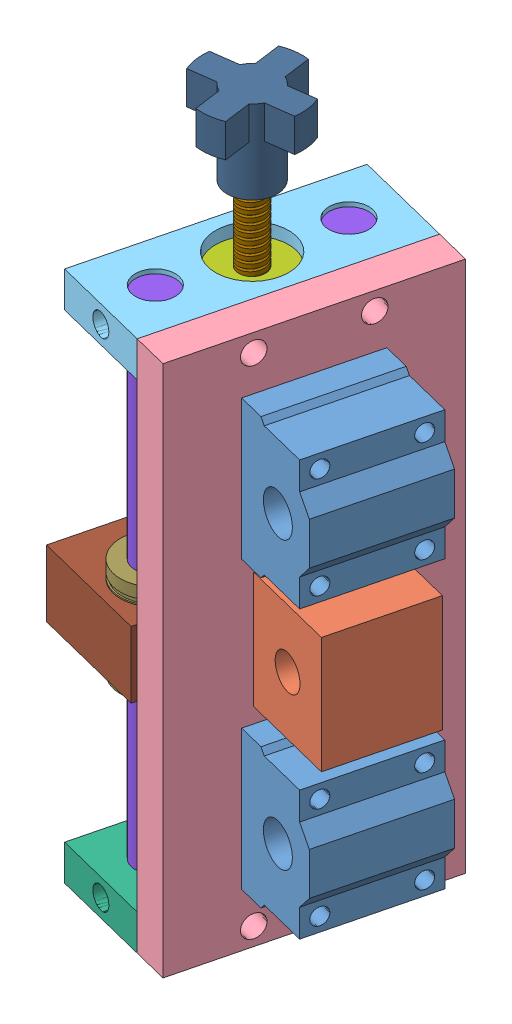
SolidWorks assembly MaquinaEixoZ, configuration Valor predeterminado. Lengths in mm.
Overall size (87.41 203.7 84.47).
17 component instances, 12 part files, 41 mates.
Components (placement in the parent):
- PillowBlockSCS12UU_12mm-5: PillowBlockSCS12UU_12mm [Valor predeterminado] at (292.0483 170.0438 408.5046) x (0 -1 0) z (0.243103 0 -0.970001) size (42 28 36)
- PillowBlockSCS12UU_12mm-6: PillowBlockSCS12UU_12mm [Valor predeterminado] at (292.0483 84.0438 408.5046) x (0 -1 0) z (0.243103 0 -0.970001) size (42 28 36)
- SuporteCastanhaTr8-2: SuporteCastanhaTr8 [Valor predeterminado] at (285.0293 127.0438 403.6528) x (0 -1 0) z (0.243103 0 -0.970001) size (35 28 30)
- CastanhaTr8_2mm-2: CastanhaTr8_2mm [Valor predeterminado] at (250.1666 126.6014 379.4525) x (0.227841 0 -0.973698) z (0 1 0) size (22 22 15.4)
- ChapaBaseEixoZ-1: ChapaBaseEixoZ [Valor predeterminado] at (264.7168 127.0438 383.0981) x (0.243103 0 -0.970001) z (0.970001 0 0.243103) size (75 160 10.7)
- ChapaBaseTraseiraEixoZ-2: ChapaBaseTraseiraEixoZ [Valor predeterminado] at (250.1668 196.3438 379.4516) x (0.243103 0 -0.970001) z (0 1 0) size (75 30 10.7)
- ChapaBaseDianteiraEixoZ-2: ChapaBaseDianteiraEixoZ [Valor predeterminado] at (250.1668 47.0438 379.4516) x (0.243103 0 -0.970001) z (0 1 0) size (75 30 10.7)
- Rolamento608zz_8mm-5: Rolamento608zz_8mm [Valor predeterminado] at (250.1668 196.3438 379.4516) x (-1 0 0) z (0 1 0) size (22 22 7)
- Rolamento608zz_8mm-6: Rolamento608zz_8mm [Valor predeterminado] at (250.1668 50.7438 379.4516) x (-1 0 0) z (0 1 0) size (22 22 7)
- EixoZHasteLinear12mm-1: EixoZHasteLinear12mm [Valor predeterminado] at (256.0013 47.7438 356.1716) x (-0.492561 0 0.870278) z (0 1 0) size (12 12 158)
- EixoZHasteLinear12mm-2: EixoZHasteLinear12mm [Valor predeterminado] at (244.3324 47.7438 402.7316) x (0.996943 0 0.078133) z (0 1 0) size (12 12 158)
- EixoZFusoTr8_2mm-1: EixoZFusoTr8_2mm [Valor predeterminado] at (250.1668 240.7438 379.4516) x (-0.951608 0 -0.307313) z (0 -1 0) size (8.21 9.24 192.92)
- AcionamentoEixoZ-1: AcionamentoEixoZ [Valor predeterminado] at (250.1668 250.7438 379.4516) x (0.991325 0 -0.131435) z (0 -1 0) size (30 30 25)
- SuporteCastanhaTr8EixoZ-2: SuporteCastanhaTr8EixoZ [Valor predeterminado] at (245.3168 110.6014 378.2361) x (0.243103 0 -0.970001) z (0 1 0) size (75 35 20)
- RolamentoLinearLM12UU12mm-2: RolamentoLinearLM12UU12mm [Valor predeterminado] at (256.0013 105.8014 356.1716) x (-0.93899 0 -0.343946) z (0 1 0) size (21 21 30)
- RolamentoLinearLM12UU12mm-3: RolamentoLinearLM12UU12mm [Valor predeterminado] at (244.3324 105.8014 402.7316) x (-0.99994 0 -0.010936) z (0 1 0) size (21 21 30)
- CastanhaTr8_2mm-4: CastanhaTr8_2mm [Valor predeterminado] at (291.35 127.0438 378.4328) x (0.970001 0 0.243103) z (0.243103 0 -0.970001) size (22 22 15.4)
Mates (geometry in assembly coordinates):
- Coincidente1: coincident anti-aligned: plane of PillowBlockSCS12UU_12mm-5 through (279.4717 191.0438 368.2393) normal (-0.970001 0 -0.243103); plane of ChapaBaseEixoZ-1 through (275.0959 127.0438 385.6993) normal (0.970001 0 0.243103)
- Concêntrico1: concentric anti-aligned: circle of PillowBlockSCS12UU_12mm-5; circle of ChapaBaseEixoZ-1
- Concêntrico2: concentric anti-aligned: circle of PillowBlockSCS12UU_12mm-5; circle of ChapaBaseEixoZ-1
- Coincidente2: coincident anti-aligned: plane of SuporteCastanhaTr8-2 through (278.7424 109.5438 371.1493) normal (-0.970001 0 -0.243103); plane of ChapaBaseEixoZ-1 through (275.0959 127.0438 385.6993) normal (0.970001 0 0.243103)
- Concêntrico3: concentric aligned: circle of SuporteCastanhaTr8-2; circle of ChapaBaseEixoZ-1
- Concêntrico4: concentric aligned: circle of SuporteCastanhaTr8-2; circle of ChapaBaseEixoZ-1
- Coincidente3: coincident anti-aligned: plane of PillowBlockSCS12UU_12mm-6 through (279.4717 105.0438 368.2393) normal (-0.970001 0 -0.243103); plane of ChapaBaseEixoZ-1 through (275.0959 127.0438 385.6993) normal (0.970001 0 0.243103)
- Concêntrico5: concentric anti-aligned: circle of PillowBlockSCS12UU_12mm-6; circle of ChapaBaseEixoZ-1
- Concêntrico6: concentric anti-aligned: circle of PillowBlockSCS12UU_12mm-6; circle of ChapaBaseEixoZ-1
- Coincidente4: coincident anti-aligned: plane of ChapaBaseEixoZ-1 through (264.7168 127.0438 383.0981) normal (-0.970001 0 -0.243103); plane of ChapaBaseTraseiraEixoZ-2 through (273.8332 207.0438 346.7231) normal (0.970001 0 0.243103)
- Concêntrico7: concentric anti-aligned: circle of ChapaBaseEixoZ-1; circle of ChapaBaseTraseiraEixoZ-2
- Concêntrico8: concentric anti-aligned: circle of ChapaBaseEixoZ-1; circle of ChapaBaseTraseiraEixoZ-2
- Coincidente7: coincident anti-aligned: plane of ChapaBaseEixoZ-1 through (264.7168 127.0438 383.0981) normal (-0.970001 0 -0.243103); plane of ChapaBaseDianteiraEixoZ-2 through (273.8332 57.7438 346.7231) normal (0.970001 0 0.243103)
- Concêntrico9: concentric anti-aligned: circle of ChapaBaseEixoZ-1; circle of ChapaBaseDianteiraEixoZ-2
- Concêntrico10: concentric anti-aligned: circle of ChapaBaseEixoZ-1; circle of ChapaBaseDianteiraEixoZ-2
- Concêntrico11: concentric anti-aligned: cylinder of ChapaBaseTraseiraEixoZ-2 through (256.0013 196.3438 356.1716) axis (0 1 0) radius 6; cylinder of EixoZHasteLinear12mm-1 through (256.0013 205.7438 356.1716) axis (0 -1 0) radius 6
- Coincidente10: coincident anti-aligned: plane of ChapaBaseDianteiraEixoZ-2 through (256.0013 47.7438 356.1716) normal (0 1 0); plane of EixoZHasteLinear12mm-1 through (256.0013 47.7438 356.1716) normal (0 -1 0)
- Concêntrico12: concentric anti-aligned: cylinder of ChapaBaseTraseiraEixoZ-2 through (244.3324 196.3438 402.7316) axis (0 1 0) radius 6; cylinder of EixoZHasteLinear12mm-2 through (244.3324 205.7438 402.7316) axis (0 -1 0) radius 6
- Coincidente11: coincident anti-aligned: plane of ChapaBaseDianteiraEixoZ-2 through (244.3324 47.7438 402.7316) normal (0 1 0); plane of EixoZHasteLinear12mm-2 through (244.3324 47.7438 402.7316) normal (0 -1 0)
- Concêntrico13: concentric anti-aligned: cylinder of ChapaBaseDianteiraEixoZ-2 through (250.1668 50.7438 379.4516) axis (0 1 0) radius 11; cylinder of Rolamento608zz_8mm-6 through (250.1668 57.7438 379.4516) axis (0 -1 0) radius 11
- Coincidente12: coincident anti-aligned: plane of ChapaBaseDianteiraEixoZ-2 through (250.1668 50.7438 379.4516) normal (0 1 0); plane of Rolamento608zz_8mm-6 through (250.1668 50.7438 379.4516) normal (0 -1 0)
- Concêntrico15: concentric anti-aligned: cylinder of ChapaBaseTraseiraEixoZ-2 through (250.1668 196.3438 379.4516) axis (0 1 0) radius 11; cylinder of Rolamento608zz_8mm-5 through (250.1668 203.3438 379.4516) axis (0 -1 0) radius 11
- Coincidente13: coincident aligned: plane of ChapaBaseTraseiraEixoZ-2 through (250.1668 196.3438 379.4516) normal (0 -1 0); plane of Rolamento608zz_8mm-5 through (250.1668 196.3438 379.4516) normal (0 -1 0)
- Concêntrico16: concentric aligned: cylinder of Rolamento608zz_8mm-5 through (250.1668 196.3438 379.4516) axis (0 1 0) radius 4; cylinder of EixoZFusoTr8_2mm-1 through (250.1668 50.7438 379.4516) axis (0 1 0) radius 4
- Coincidente14: coincident anti-aligned: plane of ChapaBaseDianteiraEixoZ-2 through (250.1668 50.7438 379.4516) normal (0 1 0); plane of EixoZFusoTr8_2mm-1 through (250.1668 50.7438 379.4516) normal (0 -1 0)
- Concêntrico17: concentric anti-aligned: cylinder of SuporteCastanhaTr8EixoZ-2 through (244.3324 110.6014 402.7316) axis (0 1 0) radius 10.5; cylinder of RolamentoLinearLM12UU12mm-3 through (244.3324 135.8014 402.7316) axis (0 -1 0) radius 10.5
- Coincidente15: coincident anti-aligned: circle of SuporteCastanhaTr8EixoZ-2; circle of RolamentoLinearLM12UU12mm-3
- Concêntrico18: concentric anti-aligned: cylinder of SuporteCastanhaTr8EixoZ-2 through (256.0013 110.6014 356.1716) axis (0 1 0) radius 10.5; cylinder of RolamentoLinearLM12UU12mm-2 through (256.0013 135.8014 356.1716) axis (0 -1 0) radius 10.5
- Coincidente16: coincident anti-aligned: circle of SuporteCastanhaTr8EixoZ-2; circle of RolamentoLinearLM12UU12mm-2
- Concêntrico19: concentric anti-aligned: cylinder of EixoZHasteLinear12mm-2 through (244.3324 205.7438 402.7316) axis (0 -1 0) radius 6; cylinder of RolamentoLinearLM12UU12mm-3 through (244.3324 105.8014 402.7316) axis (0 1 0) radius 6
- Concêntrico20: concentric anti-aligned: cylinder of EixoZHasteLinear12mm-1 through (256.0013 205.7438 356.1716) axis (0 -1 0) radius 6; cylinder of RolamentoLinearLM12UU12mm-2 through (256.0013 105.8014 356.1716) axis (0 1 0) radius 6
- Concêntrico23: concentric aligned: cylinder of CastanhaTr8_2mm-2 through (250.1666 116.6014 379.4525) axis (0 1 0) radius 5.1; cylinder of SuporteCastanhaTr8EixoZ-2 through (250.1668 110.6014 379.4516) axis (0 1 0) radius 5.15
- Concêntrico24: concentric aligned: circle of CastanhaTr8_2mm-2; circle of SuporteCastanhaTr8EixoZ-2
- Coincidente18: coincident anti-aligned: plane of CastanhaTr8_2mm-2 through (250.1666 126.6014 379.4525) normal (0 -1 0); plane of SuporteCastanhaTr8EixoZ-2 through (250.1668 126.6014 379.4516) normal (0 1 0)
- Concêntrico25: concentric aligned: cylinder of EixoZFusoTr8_2mm-1 through (250.1668 50.7438 379.4516) axis (0 1 0) radius 4; cylinder of SuporteCastanhaTr8EixoZ-2 through (250.1668 110.6014 379.4516) axis (0 1 0) radius 5.15
- Concêntrico26: concentric anti-aligned: cylinder of EixoZFusoTr8_2mm-1 through (250.1668 50.7438 379.4516) axis (0 1 0) radius 4; cylinder of AcionamentoEixoZ-1 through (250.1668 240.7438 379.4516) axis (0 -1 0) radius 4
- Coincidente19: coincident anti-aligned: plane of EixoZFusoTr8_2mm-1 through (250.1668 240.7438 379.4516) normal (0 1 0); plane of AcionamentoEixoZ-1 through (250.1668 240.7438 379.4516) normal (0 -1 0)
- DistânciaLimite2: limit distance = 48.0575 mm anti-aligned: plane of RolamentoLinearLM12UU12mm-3 through (244.3324 105.8014 402.7316) normal (0 -1 0); plane of ChapaBaseDianteiraEixoZ-2 through (250.1668 57.7438 379.4516) normal (0 1 0)
- Concêntrico28: concentric aligned: cylinder of SuporteCastanhaTr8-2 through (285.0293 127.0438 403.6528) axis (0.243103 0 -0.970001) radius 5.15; cylinder of CastanhaTr8_2mm-4 through (288.919 127.0438 388.1328) axis (0.243103 0 -0.970001) radius 5.1
- Concêntrico29: concentric aligned: circle of SuporteCastanhaTr8-2; circle of CastanhaTr8_2mm-4
- Coincidente22: coincident anti-aligned: plane of SuporteCastanhaTr8-2 through (291.35 127.0438 378.4328) normal (0.243103 0 -0.970001); plane of CastanhaTr8_2mm-4 through (291.35 127.0438 378.4328) normal (-0.243103 0 0.970001)
